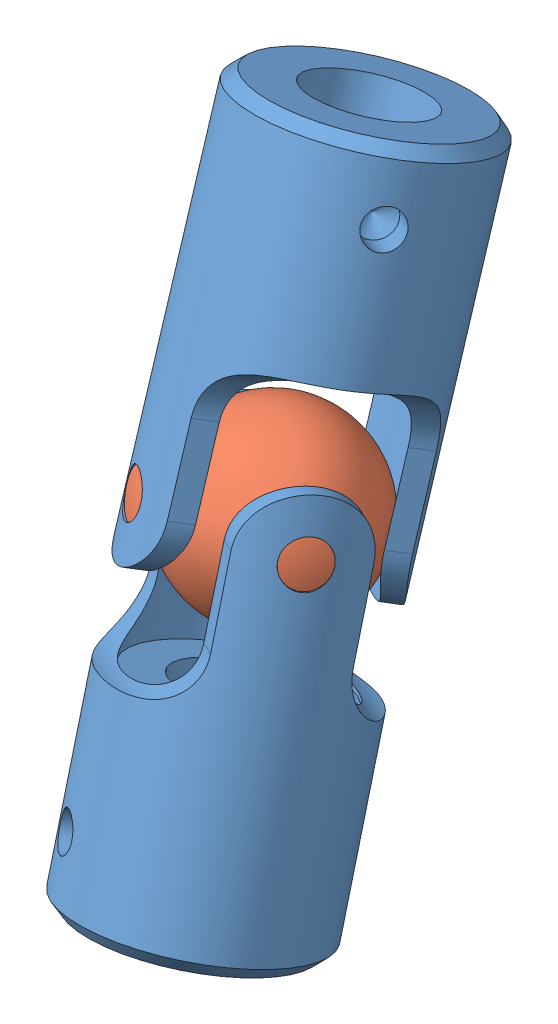
SolidWorks assembly ASSY_BERG_UJ3_U-JOINT_0250 SHAFT, configuration Default. Lengths in mm.
Overall size (49.87 104.91 73.91).
3 component instances, 2 part files, 9 mates.
Components (placement in the parent):
- UJ-3_YOKE-1: UJ-3_YOKE [Default] at (1.2782 -17.1564 5.9295) x (-0.067274 0.942733 -0.326694) z (-0.55309 0.237283 0.798617) size (55.56 31.75 31.75)
- UJ-3_BALL-1: UJ-3_BALL [Default] x (-0.047159 0.933502 -0.355458) z (-0.830401 -0.234417 -0.505453) size (26.46 31.75 31.75)
- UJ-3_YOKE-3: UJ-3_YOKE [Default] at (-1.0941 16.9344 -6.5701) x (0.057071 -0.930636 0.361468) z (0.829779 0.245546 0.501173) size (55.56 31.75 31.75)
Mates (geometry in assembly coordinates):
- Coincident11: coincident: point of UJ-3_BALL-1; plane of assembly
- Coincident12: coincident: point of UJ-3_BALL-1; plane of assembly
- Coincident13: coincident: point of UJ-3_BALL-1; plane of assembly
- Coincident15: coincident aligned: axis of UJ-3_YOKE-1 through (-13.8959 -3.9227 -8.4583) axis (0.830401 0.234417 0.505453); axis of UJ-3_BALL-1 through (-14.5418 -4.1051 -8.8514) axis (0.830401 0.234417 0.505453)
- Coincident17: coincident anti-aligned: axis of UJ-3_BALL-1 through (7.1297 -3.4846 -10.0972) axis (0.555167 -0.271336 -0.786236); axis of UJ-3_YOKE-3 through (9.2902 -4.5405 -13.1569) axis (-0.555167 0.271336 0.786236)
- Parallel1: parallel anti-aligned: plane of UJ-3_YOKE-1; plane of UJ-3_YOKE-3
- Tangent6: tangent aligned: cylinder of UJ-3_YOKE-1 through (-2.1359 29.9318 -10.3725) axis (0.067274 -0.942733 0.326694) radius 15.875; sphere of UJ-3_BALL-1
- Tangent7: tangent aligned: sphere of UJ-3_BALL-1; cylinder of UJ-3_YOKE-3 through (1.812 -29.5477 11.4766) axis (-0.057071 0.930636 -0.361468) radius 15.875
- LimitAngle1: limit planar angle = 0.038208 rad anti-aligned: plane of UJ-3_YOKE-3 through (-2.718 44.3215 -17.2149) normal (-0.057071 0.930636 -0.361468); plane of UJ-3_YOKE-1 through (3.2039 -44.8977 15.5588) normal (0.067274 -0.942733 0.326694)
